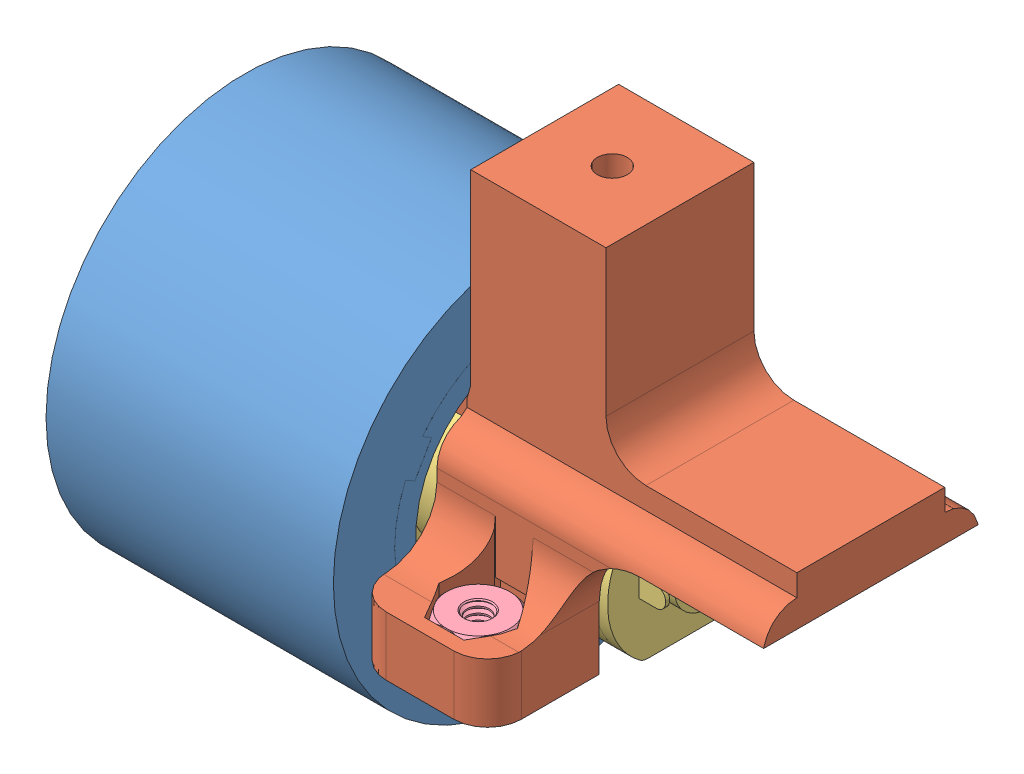
SolidWorks assembly wheelAssembly, configuration Default. Lengths in mm.
Overall size (46.98 37.58 29.84).
4 component instances, 4 part files, 9 mates.
Components (placement in the parent):
- cobra_wheels-1: cobra_wheels [Default] at (-14.3422 21.8586 32.0862) size (21.59 29.84 29.84)
- DualMotorMount-1: DualMotorMount [Default] at (18.2958 28.916 25.9577) x (0 0 1) z (0 -1 0) size (28.89 39.74 27.5)
- Pololu - 1_250 Micro gear motor-1: Pololu - 1_250 Micro gear motor [Default] at (11.4278 21.8586 32.0862) x (0 0 1) z (-1 0 0) size (12 10 35.27)
- 90480A003-1: 90480A003 [90480A003] at (13.9492 19.81 42.8312) x (0.866025 0 0.5) z (-0.5 0 0.866025) size (4.76 1.59 6.05)
Mates (geometry in assembly coordinates):
- Coincident2: coincident aligned: plane of cobra_wheels-1 through (-14.3422 11.4954 42.5288) normal (-1 0 0); plane of Pololu - 1_250 Micro gear motor-1 through (-14.3422 21.8586 30.6162) normal (-1 0 0)
- Concentric1: concentric anti-aligned: circle of cobra_wheels-1; cylinder of Pololu - 1_250 Micro gear motor-1 through (11.4278 21.8586 32.0862) axis (1 0 0) radius 1.47
- Coincident4: coincident anti-aligned: plane of DualMotorMount-1 through (18.2958 26.8586 25.9577) normal (0 -1 0); plane of Pololu - 1_250 Micro gear motor-1 through (3.9278 26.8586 35.4029) normal (0 1 0)
- Coincident5: coincident anti-aligned: plane of DualMotorMount-1 through (-5.0722 24.3186 27.6595) normal (1 0 0); plane of Pololu - 1_250 Micro gear motor-1 through (-5.0722 17.8586 27.0862) normal (-1 0 0)
- Coincident6: coincident anti-aligned: plane of DualMotorMount-1 through (18.2958 28.916 38.0862) normal (0 0 -1); plane of Pololu - 1_250 Micro gear motor-1 through (2.9278 17.8586 38.0862) normal (0 0 1)
- Coincident8: coincident anti-aligned: plane of DualMotorMount-1 through (18.2958 19.81 38.0862) normal (0 1 0); plane of 90480A003-1 through (15.324 19.81 40.4499) normal (0 -1 0)
- Concentric2: concentric aligned: cylinder of DualMotorMount-1 through (13.9492 21.461 42.8312) axis (0 -1 0) radius 1.27; circle of 90480A003-1
- Parallel1: parallel anti-aligned: plane of DualMotorMount-1 through (10.9992 19.81 42.8312) normal (0.866025 0 0.5); plane of 90480A003-1 through (12.5744 21.3975 40.4499) normal (-0.866025 0 -0.5)
- Parallel2: parallel aligned: plane of DualMotorMount-1 through (18.2958 44.516 25.9577) normal (0 1 0); plane of assembly through (0 0 0) normal (0 1 0)
